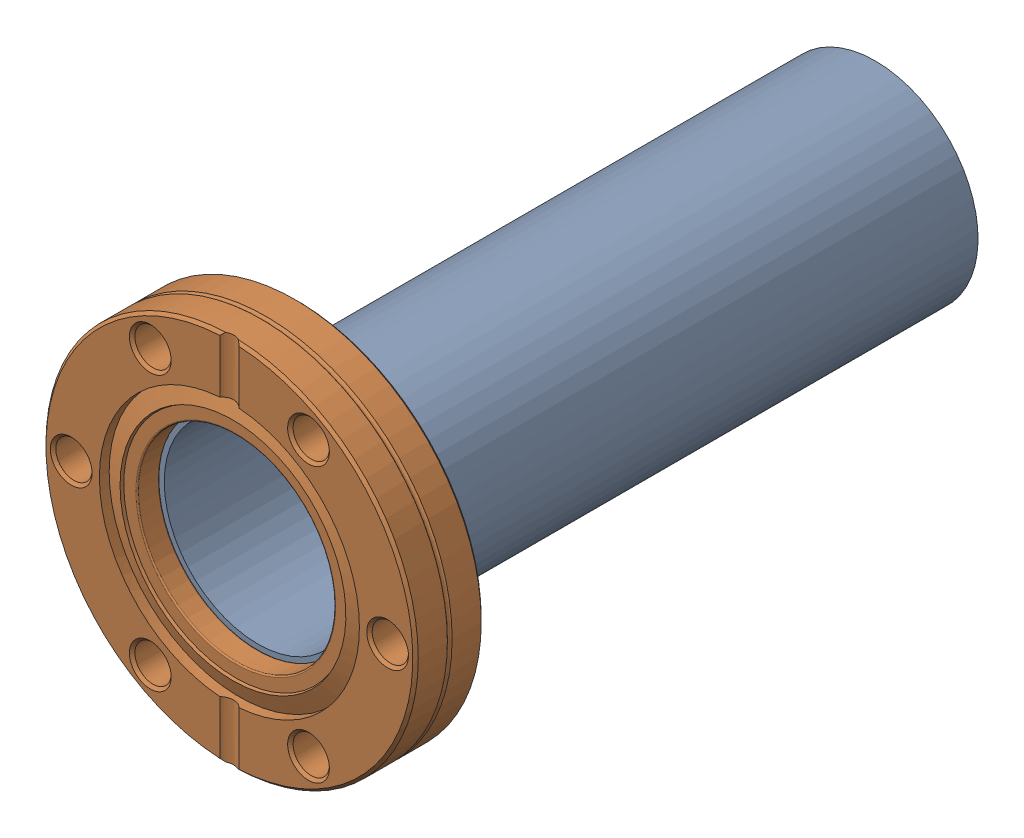
SolidWorks assembly Er Source P2-2_A0001676, configuration Default. Lengths in mm.
Overall size (69.09 69.09 120.02).
2 component instances, 2 part files, 0 mates.
Components (placement in the parent):
- Er Source P2-2-2_P0001614-1: Er Source P2-2-2_P0001614 [Default] at (0 0 -56.2483) x (0 1 0) z (0 0 -1) size (38.1 38.1 114.58)
- Er Source P2-2-1_P0000127-1: Er Source P2-2-1_P0000127 [Default] at origin size (69.09 69.09 12.84)
